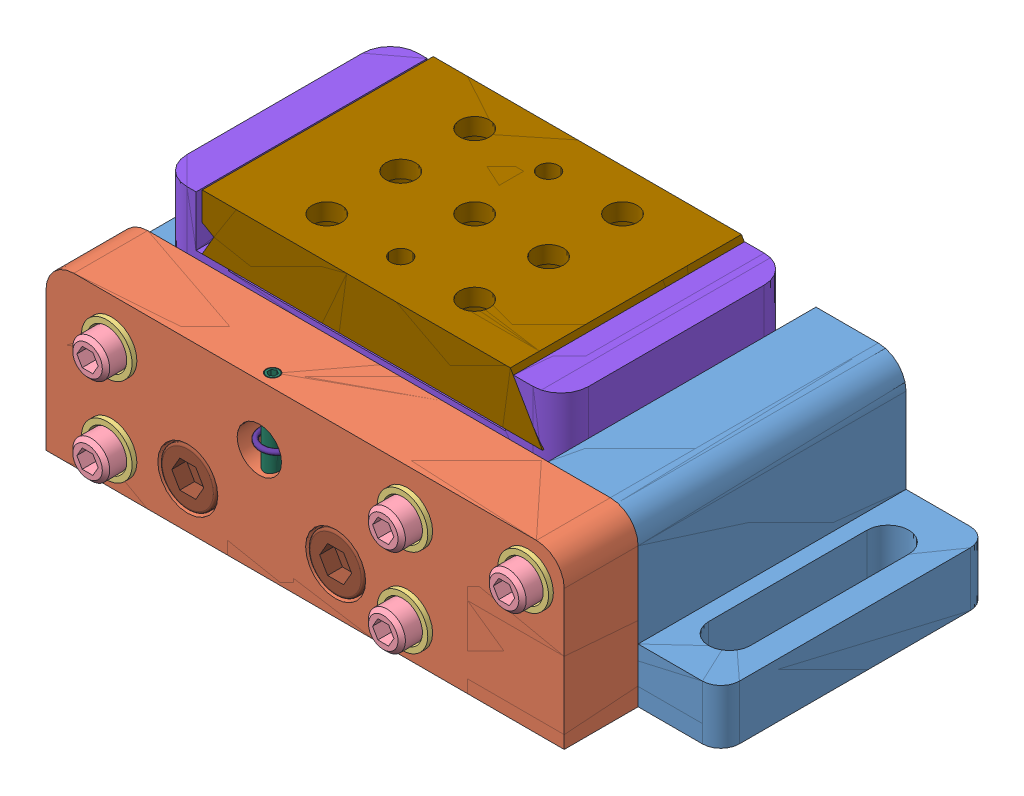
SolidWorks assembly newfocus_9081_5axis_stage, configuration Default. Lengths in mm.
Overall size (117.47 34.33 62.84).
50 component instances, 18 part files, 0 mates.
Components (placement in the parent):
- 400431_-1: 400431_ [Default] at (-54.4322 0 -15.6523) x (1 0 0) z (0 1 0) size (117.47 46.03 28.73)
- 400431_-2: 400431_ [Default] at (-54.4322 0 -15.6523) x (1 0 0) z (0 1 0) size (117.47 46.03 28.73)
- 900451_-1: 900451_ [Default] at (-40.2082 0 -15.6523) x (1 0 0) z (0 1 0) size (89.03 12.7 28.73)
- 900451_-2: 900451_ [Default] at (-40.2082 0 -15.6523) x (1 0 0) z (0 1 0) size (89.03 12.7 28.73)
- 900840_01_-1: 900840_01_ [Default] at (42.5958 22.3774 45.2374) x (0 0 1) z (0 1 0) size (14.3 10.31 10.31)
- 900840_01_-2: 900840_01_ [Default] at (21.844 21.1074 45.2374) x (0 0 1) z (0 1 0) size (14.3 10.31 10.31)
- 900840_01_-3: 900840_01_ [Default] at (-28.956 21.1074 45.2374) x (0 0 1) z (0 1 0) size (14.3 10.31 10.31)
- 900840_01_-4: 900840_01_ [Default] at (-28.956 5.9944 45.2374) x (0 0 1) z (0 1 0) size (14.3 10.31 10.31)
- 900840_01_-5: 900840_01_ [Default] at (21.844 5.9944 45.2374) x (0 0 1) z (0 1 0) size (14.3 10.31 10.31)
- 900809_01_-1: 900809_01_ [Default] at (42.5958 22.3774 62.8396) x (0 0 -1) z (0 1 0) size (21.94 6.35 6.35)
- 900809_01_-2: 900809_01_ [Default] at (21.844 21.1074 62.8396) x (0 0 -1) z (0 1 0) size (21.94 6.35 6.35)
- 900809_01_-3: 900809_01_ [Default] at (-28.956 21.1074 62.8396) x (0 0 -1) z (0 1 0) size (21.94 6.35 6.35)
- 900809_01_-4: 900809_01_ [Default] at (21.844 5.9944 62.8396) x (0 0 -1) z (0 1 0) size (21.94 6.35 6.35)
- 900809_01_-5: 900809_01_ [Default] at (-28.956 5.9944 62.8396) x (0 0 -1) z (0 1 0) size (21.94 6.35 6.35)
- 400424_-1: 400424_ [Default] at (42.5958 22.3774 40.9004) x (0 -1 0) z (0 0 -1) size (9.5 9.5 32.9)
- 400424_-2: 400424_ [Default] at (21.844 5.9944 40.9004) x (-1 0 0) z (0 0 -1) size (9.5 9.5 32.9)
- 400425_-1: 400425_ [Default] at (-28.956 5.9944 40.9004) x (-1 0 0) z (0 0 -1) size (9.5 9.5 32.9)
- 001097_-1: 001097_ [Default] at (-28.956 13.4388 35.7632) x (0 1 0) z (0 0 1) size (9.53 9.53 9.53)
- 001097_-2: 001097_ [Default] at (-28.956 13.4388 10.3632) x (0 1 0) z (0 0 1) size (9.53 9.53 9.53)
- 001097_-3: 001097_ [Default] at (21.844 13.4388 23.0632) x (0 1 0) z (0 0 -1) size (9.53 9.53 9.53)
- 001097_-4: 001097_ [Default] at (35.1807 22.3774 23.0124) x (-1 0 0) z (0 0 1) size (9.53 9.53 9.53)
- 400435_-1: 400435_ [Default] at (-38.5936 18.2013 -14.4521) x (1 0 0) z (0 1 0) size (70.77 39.7 15.32)
- 400435_-2: 400435_ [Default] at (-38.5936 18.2013 -14.4521) x (1 0 0) z (0 1 0) size (70.77 39.7 15.32)
- 400434_-1: 400434_ [Default] at (-31.2022 24.8053 -14.4521) x (1 0 0) z (0 1 0) size (58.45 39.7 9.53)
- 400434_-2: 400434_ [Default] at (-31.2022 24.8053 -14.4521) x (1 0 0) z (0 1 0) size (58.45 39.7 9.53)
- 001101_-1: 001101_ [Default] at (44.958 22.3774 1.5748) x (-1 0 0) z (0 1 0) size (3.18 15.88 3.18)
- 001101_-2: 001101_ [Default] at (21.844 3.6322 1.5748) x (-1 0 0) z (0 1 0) size (3.18 15.88 3.18)
- 001101_-3: 001101_ [Default] at (-28.956 3.6322 1.5748) x (-1 0 0) z (0 1 0) size (3.18 15.88 3.18)
- 001098_-1: 001098_ [Default] at (-15.8496 7.9502 52.3748) x (-1 0 0) z (0 1 0) size (9.53 22.23 9.53)
- 001098_-2: 001098_ [Default] at (9.5504 7.9502 52.3748) x (-1 0 0) z (0 1 0) size (9.53 22.23 9.53)
- 001158_-1: 001158_ [Default] at (-4.202 24.8053 36.8363) size (2.84 6.35 2.84)
- 001158_-2: 001158_ [Default] at (-4.202 24.8053 36.8363) size (2.84 6.35 2.84)
- 001009_-1: 001009_ [Default] at (-37.9664 30.4122 21.0375) x (0.5 0.866025 0) z (0 0 1) size (3.51 8.66 3.51)
- 001009_-2: 001009_ [Default] at (-37.9664 30.4122 21.0375) x (0.5 0.866025 0) z (0 0 1) size (3.51 8.66 3.51)
- 001096_-1: 001096_ [Default] at (0 7.9248 38.9128) x (-1 0 0) z (0 1 0) size (2.84 12.7 2.84)
- 001096_-2: 001096_ [Default] at (0 7.9248 38.9128) x (-1 0 0) z (0 1 0) size (2.84 12.7 2.84)
- 001096_-3: 001096_ [Default] at (-12.5586 20.7413 37.5984) x (-1 0 0) z (0 1 0) size (2.84 12.7 2.84)
- 001096_-4: 001096_ [Default] at (-12.5586 20.7413 37.5984) x (-1 0 0) z (0 1 0) size (2.84 12.7 2.84)
- 001096_-5: 001096_ [Default] at (0 7.9248 7.112) x (1 0 0) z (0 1 0) size (2.84 12.7 2.84)
- 001096_-6: 001096_ [Default] at (0 7.9248 7.112) x (1 0 0) z (0 1 0) size (2.84 12.7 2.84)
- 001096_-7: 001096_ [Default] at (-12.5586 20.7413 4.5022) x (1 0 0) z (0 1 0) size (2.84 12.7 2.84)
- 001096_-8: 001096_ [Default] at (-12.5586 20.7413 4.5022) x (1 0 0) z (0 1 0) size (2.84 12.7 2.84)
- 001182_-1: 001182_ [Default] at (-3.556 28.7274 56.4388) size (2.84 15.88 2.84)
- 001182_-2: 001182_ [Default] at (-3.556 28.7274 56.4388) size (2.84 15.88 2.84)
- 001735_-1: 001735_ [Default] at (44.958 22.3774 39.0462) size (3.14 3.15 26.01)
- 001735_-2: 001735_ [Default] at (21.844 3.6322 39.0462) size (3.14 3.15 26.01)
- 001735_-3: 001735_ [Default] at (-28.956 3.6322 39.0462) size (3.14 3.15 26.01)
- 001012_-1: 001012_ [Default] at (-3.556 18.415 54.2798) size (6.46 6.49 24.77)
- 001172_-1: 001172_ [Default] at (-11.9236 19.6415 13.1635) x (0.866025 0.5 0) z (-0.5 0.866025 0) size (4.86 4.88 20.02)
- 001172_-2: 001172_ [Default] at (-11.9236 19.6415 29.0386) x (0.866025 0.5 0) z (-0.5 0.866025 0) size (4.86 4.88 20.02)
